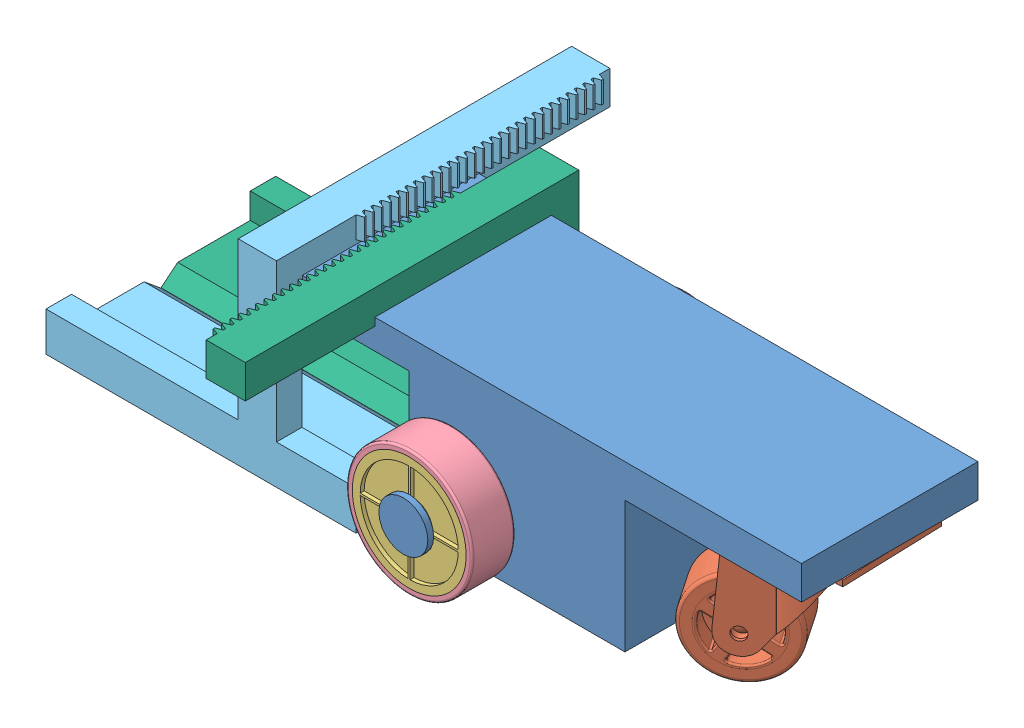
SolidWorks assembly rocr, configuration Default. Lengths in mm.
Overall size (382.03 132.32 272.84).
8 component instances, 6 part files, 14 mates.
Components (placement in the parent):
- base_plate_diff-1: base_plate_diff [Default] at origin size (283 84.05 147)
- miniCasterWheel-1: miniCasterWheel [Default] at (-37 -18.4896 45) x (0.99948 0 -0.032244) z (0.032244 0 0.99948) size (84.67 81.88 62.16)
- wheel_diff-1: wheel_diff [Default] at (-175 -41.9468 115) x (-0.999997 0.002359 0) z (0 0 -1) size (62.6 60 22)
- tyre_diff-1: tyre_diff [Default] at (-175 -41.9468 93) size (64 64 22)
- wheel_diff-2: wheel_diff [Default] at (-175 -41.9468 -26) x (0.919997 0.391925 0) z (0 0 1) size (62.6 60 22)
- tyre_diff-2: tyre_diff [Default] at (-175 -41.9468 -26) size (64 64 22)
- right_arm_final_diff-1: right_arm_final_diff [Default] at (-214 -72 103.1853) size (158 100 170)
- left_arm_final_diff-1: left_arm_final_diff [Default] at (-367.53 -72 -13.9771) size (162.5 100 170)
Mates (geometry in assembly coordinates):
- Concentric1: concentric aligned: cylinder of base_plate_diff-1 through (-175 -41.9468 87) axis (0 0 1) radius 10; cylinder of wheel_diff-1 through (-175 -41.9468 49) axis (0 0 1) radius 10
- Coincident4: coincident anti-aligned: plane of base_plate_diff-1 through (-175 -41.9468 115) normal (0 0 -1); plane of wheel_diff-1 through (-175 -41.9468 115) normal (0 0 1)
- Concentric2: concentric anti-aligned: cylinder of wheel_diff-1 through (-175 -41.9468 93) axis (0 0 1) radius 30; cylinder of tyre_diff-1 through (-175 -41.9468 115) axis (0 0 -1) radius 30
- Coincident5: coincident aligned: plane of wheel_diff-1 through (-175 -41.9468 115) normal (0 0 1); plane of tyre_diff-1 through (-175 -41.9468 115) normal (0 0 1)
- Concentric3: concentric aligned: cylinder of base_plate_diff-1 through (-175 -41.9468 2) axis (0 0 -1) radius 10; cylinder of wheel_diff-2 through (-175 -41.9468 40) axis (0 0 -1) radius 10
- Coincident6: coincident anti-aligned: plane of base_plate_diff-1 through (-175 -41.9468 -26) normal (0 0 1); plane of wheel_diff-2 through (-175 -41.9468 -26) normal (0 0 -1)
- Concentric4: concentric aligned: cylinder of wheel_diff-2 through (-175 -41.9468 -4) axis (0 0 -1) radius 30; cylinder of tyre_diff-2 through (-175 -41.9468 -4) axis (0 0 -1) radius 30
- Coincident7: coincident aligned: plane of wheel_diff-2 through (-175 -41.9468 -26) normal (0 0 -1); plane of tyre_diff-2 through (-175 -41.9468 -26) normal (0 0 -1)
- Coincident8: coincident anti-aligned: plane of base_plate_diff-1 through (-254.5 11 90) normal (0 1 0); plane of right_arm_final_diff-1 through (-214 11 103.1853) normal (0 -1 0)
- Coincident9: coincident anti-aligned: plane of base_plate_diff-1 through (-274 11 90) normal (1 0 0); plane of right_arm_final_diff-1 through (-274 -72 -11.6982) normal (-1 0 0)
- Coincident10: coincident anti-aligned: plane of base_plate_diff-1 through (-217.53 11 90) normal (0 1 0); plane of left_arm_final_diff-1 through (-367.53 11 -13.9771) normal (0 -1 0)
- Coincident11: coincident anti-aligned: plane of base_plate_diff-1 through (-237.53 11 90) normal (1 0 0); plane of left_arm_final_diff-1 through (-237.53 -72 101.0033) normal (-1 0 0)
- Concentric5: concentric aligned: cylinder of base_plate_diff-1 through (-37 4.9532 45) axis (0 -1 0) radius 10; cylinder of miniCasterWheel-1 through (-37 7.9532 45) axis (0 -1 0) radius 10
- Coincident12: coincident anti-aligned: plane of base_plate_diff-1 through (-37 7.9532 45) normal (0 -1 0); plane of miniCasterWheel-1 through (-37 7.9532 45) normal (0 1 0)
